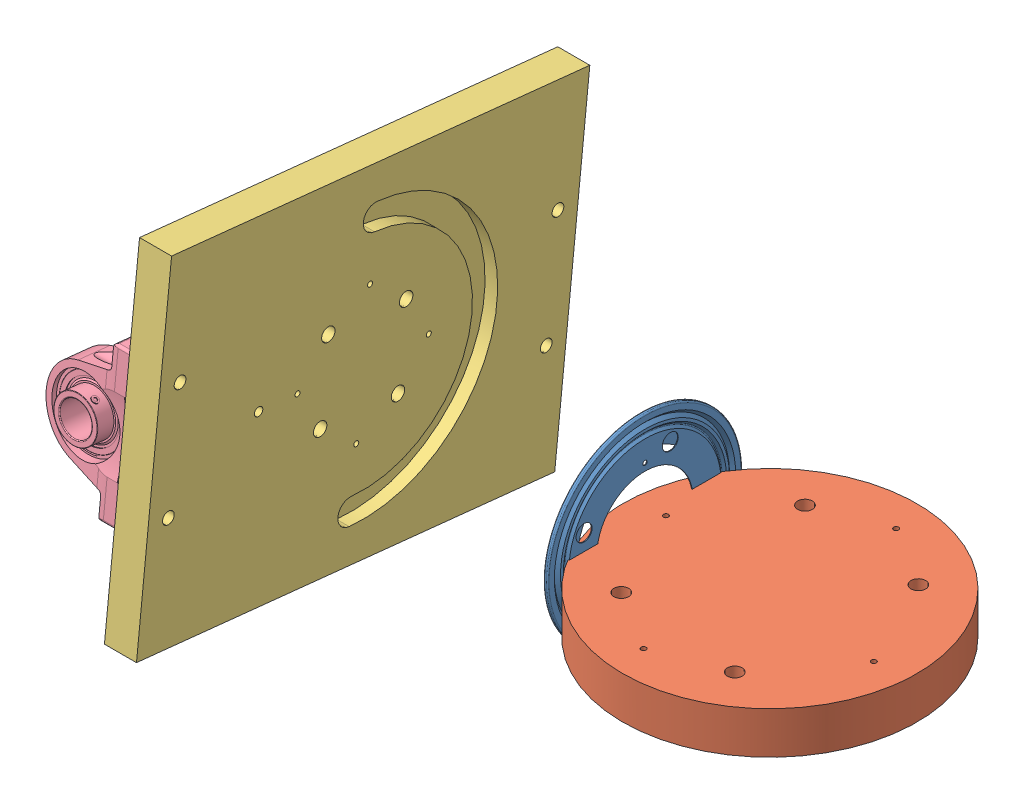
SolidWorks assembly turntable assembly, configuration Default. Lengths in mm.
Overall size (811.7 452.38 561.94).
5 component instances, 4 part files, 1 mates.
Components (placement in the parent):
- turntable-1: turntable [Default] at (-141.0814 -10.4682 81.5587) size (8.13 231.52 231.52)
- Rotary table top plate-1: Rotary table top plate [Default] at (11.3999 -30 81.5587) x (0.096436 0 -0.995339) z (0.995339 0 0.096436) size (350 50 350)
- Rotory table bottom table-1: Rotory table bottom table [Default] at (-510.2425 -10.4682 81.5587) x (0 -0.994544 0.104317) z (0 0.104317 0.994544) size (400 38.1 523.07)
- 2773T700-1: 2773T700 [2773T7] at (-559.4425 -34.0153 -142.6875) x (0 -0.09899 -0.995088) z (0 0.995088 -0.09899) size (55.56 99 175)
- 2773T700-2: 2773T700 [2773T7] at (-559.4425 13.0711 306.219) x (0 0.104042 0.994573) z (0 -0.994573 0.104042) size (55.56 99 175)
Mates (geometry in assembly coordinates):
- Coincident7: coincident aligned: plane of Rotary table top plate-1 through (11.3999 0 81.5587) normal (0 1 0); plane of assembly through (0 0 0) normal (0 1 0)
